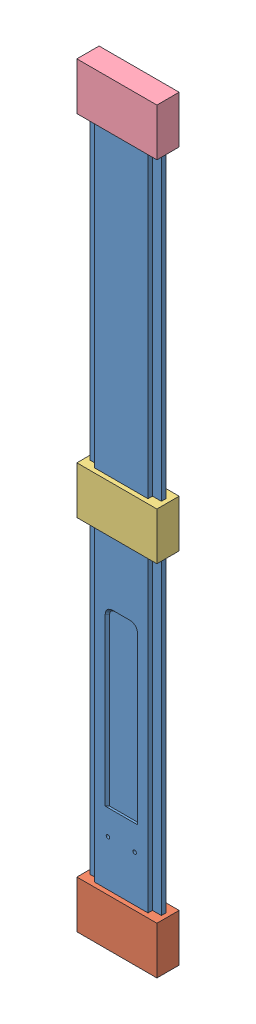
SolidWorks assembly demo of gluing blocks, configuration Default. Lengths in mm.
Overall size (57.15 539.75 15.87).
6 component instances, 6 part files, 15 mates.
Components (placement in the parent):
- zedd-blade-1: zedd-blade [Default] at (285.1811 376.3781 297.4145) size (50.8 533.4 9.52)
- bottom block-1: bottom block [Default] at (233.6811 128.8031 547.8755) x (-1 0 0) z (0 0 -1) size (57.15 33.87 15.88)
- middle block-1: middle block [Default] at (233.6811 351.0531 547.8755) size (57.15 33.87 15.88)
- top block-1: top block [Default] at (233.6811 566.9531 547.8755) size (57.15 33.87 15.88)
- drilling small-1: drilling small [Default] at (233.6811 78.0031 552.638) size (44.45 76.2 6.35) (hidden)
- drilling big-1: drilling big [Default] at (233.6811 78.0031 549.463) size (57.15 76.2 6.35) (hidden)
Mates (geometry in assembly coordinates):
- Coincident1: coincident anti-aligned: plane of zedd-blade-1 through (222.2811 614.5781 549.463) normal (0 1 0); plane of top block-1 through (233.6811 614.5781 547.8755) normal (0 -1 0)
- Coincident2: coincident anti-aligned: plane of zedd-blade-1 through (208.2811 600.5781 549.463) normal (-1 0 0); plane of top block-1 through (208.2811 464.4679 547.8755) normal (1 0 0)
- Coincident3: coincident anti-aligned: plane of zedd-blade-1 through (285.1811 376.3781 543.113) normal (0 0 -1); plane of top block-1 through (233.6811 464.4679 543.113) normal (0 0 1)
- Coincident5: coincident aligned: plane of middle block-1 through (262.2561 401.8531 539.938) normal (1 0 0); plane of top block-1 through (262.2561 617.7531 539.938) normal (1 0 0)
- Coincident6: coincident aligned: plane of middle block-1 through (205.1061 401.8531 539.938) normal (0 0 -1); plane of top block-1 through (205.1061 617.7531 539.938) normal (0 0 -1)
- Distance1: distance = 215.9 mm anti-aligned: plane of middle block-1 through (262.2561 367.9865 539.928) normal (0 1 0); plane of top block-1 through (262.2561 583.8865 539.928) normal (0 -1 0)
- Coincident8: coincident anti-aligned: plane of zedd-blade-1 through (208.2811 81.1781 549.463) normal (0 -1 0); plane of bottom block-1 through (233.6811 81.1781 547.8755) normal (0 1 0)
- Coincident9: coincident aligned: plane of bottom block-1 through (262.2561 179.6031 555.813) normal (0 0 1); plane of middle block-1 through (205.1061 401.8531 555.813) normal (0 0 1)
- Coincident10: coincident aligned: plane of bottom block-1 through (205.1061 179.6031 555.813) normal (-1 0 0); plane of middle block-1 through (205.1061 401.8531 539.938) normal (-1 0 0)
- Coincident12: coincident: plane of zedd-blade-1 through (285.1811 376.3781 552.638) normal (0 0 1); plane of drilling small-1 through (214.6311 39.7711 552.638) normal (0 0 -1)
- Coincident13: coincident: plane of zedd-blade-1 through (214.6311 376.3781 552.638) normal (-1 0 0); plane of drilling small-1 through (214.6311 39.7711 549.463) normal (1 0 0)
- Coincident14: coincident anti-aligned: plane of zedd-blade-1 through (208.2811 81.1781 549.463) normal (0 -1 0); plane of drilling small-1 through (233.6811 81.1781 552.638) normal (0 1 0)
- Coincident15: coincident: plane of zedd-blade-1 through (245.0811 600.5781 549.463) normal (0 0 1); plane of drilling big-1 through (195.343 27.104 549.463) normal (0 0 -1)
- Coincident16: coincident: plane of zedd-blade-1 through (208.2811 81.1781 549.463) normal (0 -1 0); plane of drilling big-1 through (233.6811 81.1781 549.463) normal (0 1 0)
- Coincident17: coincident anti-aligned: plane of zedd-blade-1 through (208.2811 600.5781 549.463) normal (-1 0 0); plane of drilling big-1 through (208.2811 27.104 546.288) normal (1 0 0)
